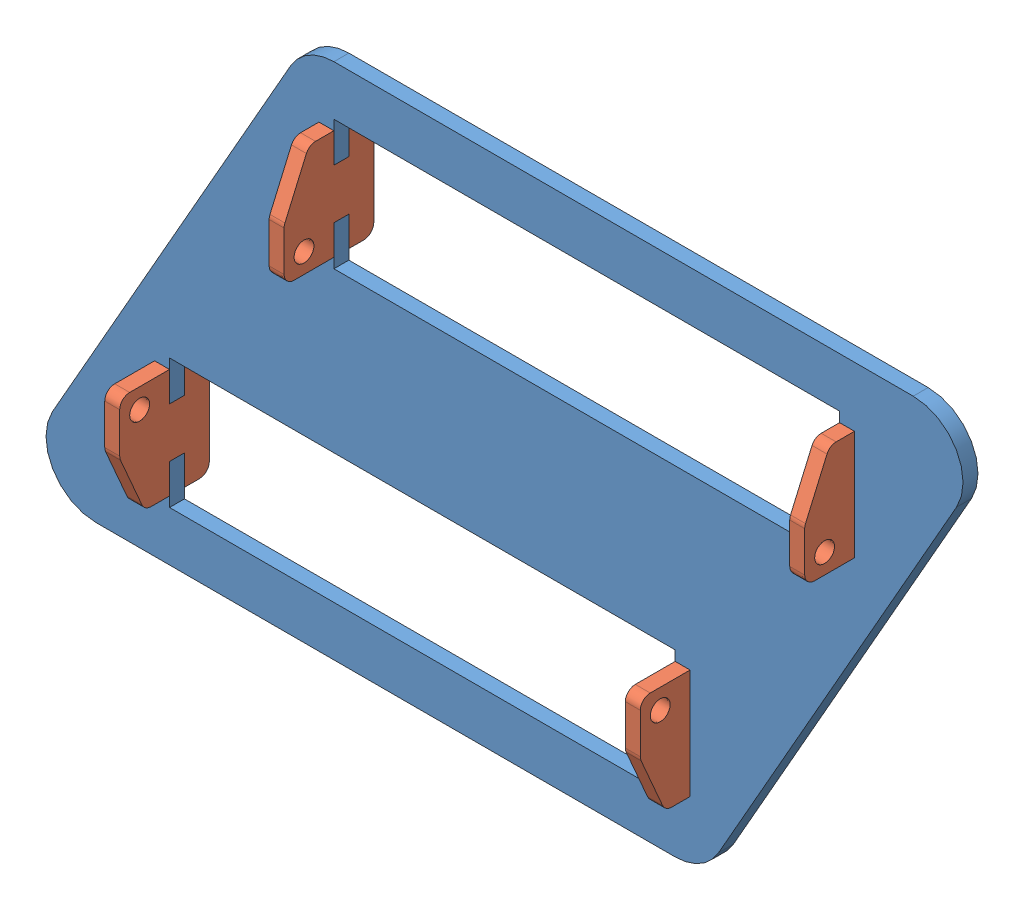
SolidWorks assembly 2 disk elch, configuration Standard. Lengths in mm.
Overall size (184.09 104 18).
5 component instances, 2 part files, 12 mates.
Components (placement in the parent):
- 2 disk frame-1: 2 disk frame [Standard] at (-123.4433 -54.4438 184.0862) size (184.09 104 3)
- hdd_mount-1: hdd_mount [3mm] at (-94.4553 -31.4438 179.0862) x (0 1 0) z (1 0 0) size (22 18 3)
- hdd_mount-2: hdd_mount [3mm] at (10.0447 -31.4438 179.0862) x (0 1 0) z (1 0 0) size (22 18 3)
- hdd_mount-3: hdd_mount [3mm] at (-58.4553 26.5562 179.0862) x (0 -1 0) z (-1 0 0) size (22 18 3)
- hdd_mount-4: hdd_mount [3mm] at (46.0447 26.5562 179.0862) x (0 -1 0) z (-1 0 0) size (22 18 3)
Mates (geometry in assembly coordinates):
- Deckungsgleich1: coincident anti-aligned: plane of 2 disk frame-1 through (-94.4553 -36.4438 184.0852) normal (1 0 0); plane of hdd_mount-1 through (-94.4553 -31.4438 179.0862) normal (-1 0 0)
- Deckungsgleich2: coincident anti-aligned: plane of 2 disk frame-1 through (-123.4433 -54.4438 187.0862) normal (0 0 1); plane of hdd_mount-1 through (-91.4553 -36.4438 187.0862) normal (0 0 -1)
- Deckungsgleich3: coincident anti-aligned: plane of 2 disk frame-1 through (-91.4553 -36.4438 184.0852) normal (0 1 0); plane of hdd_mount-1 through (-91.4553 -36.4438 187.0862) normal (0 -1 0)
- Deckungsgleich4: coincident anti-aligned: plane of 2 disk frame-1 through (13.0447 -36.4438 184.0852) normal (-1 0 0); plane of hdd_mount-2 through (13.0447 -31.4438 179.0862) normal (1 0 0)
- Deckungsgleich5: coincident anti-aligned: plane of 2 disk frame-1 through (-123.4433 -54.4438 187.0862) normal (0 0 1); plane of hdd_mount-2 through (13.0447 -26.4438 187.0862) normal (0 0 -1)
- Deckungsgleich6: coincident anti-aligned: plane of 2 disk frame-1 through (10.0447 -36.4438 184.0852) normal (0 1 0); plane of hdd_mount-2 through (13.0447 -36.4438 187.0862) normal (0 -1 0)
- Deckungsgleich8: coincident anti-aligned: plane of 2 disk frame-1 through (43.0447 21.5562 184.0852) normal (0 1 0); plane of hdd_mount-4 through (43.0447 21.5562 187.0862) normal (0 -1 0)
- Deckungsgleich9: coincident anti-aligned: plane of 2 disk frame-1 through (-123.4433 -54.4438 184.0862) normal (0 0 -1); plane of hdd_mount-4 through (43.0447 31.5562 184.0862) normal (0 0 1)
- Deckungsgleich10: coincident anti-aligned: plane of 2 disk frame-1 through (46.0447 21.5562 184.0852) normal (-1 0 0); plane of hdd_mount-4 through (46.0447 36.5562 179.0862) normal (1 0 0)
- Deckungsgleich11: coincident: plane of 2 disk frame-1 through (-61.4553 21.5562 184.0852) normal (1 0 0); plane of hdd_mount-3 through (-61.4553 26.5562 179.0862) normal (-1 0 0)
- Deckungsgleich12: coincident: plane of 2 disk frame-1 through (-61.4553 31.5562 184.0852) normal (0 -1 0); plane of hdd_mount-3 through (-61.4553 31.5562 187.0862) normal (0 1 0)
- Deckungsgleich13: coincident anti-aligned: plane of 2 disk frame-1 through (-123.4433 -54.4438 184.0862) normal (0 0 -1); plane of hdd_mount-3 through (-61.4553 31.5562 184.0862) normal (0 0 1)
